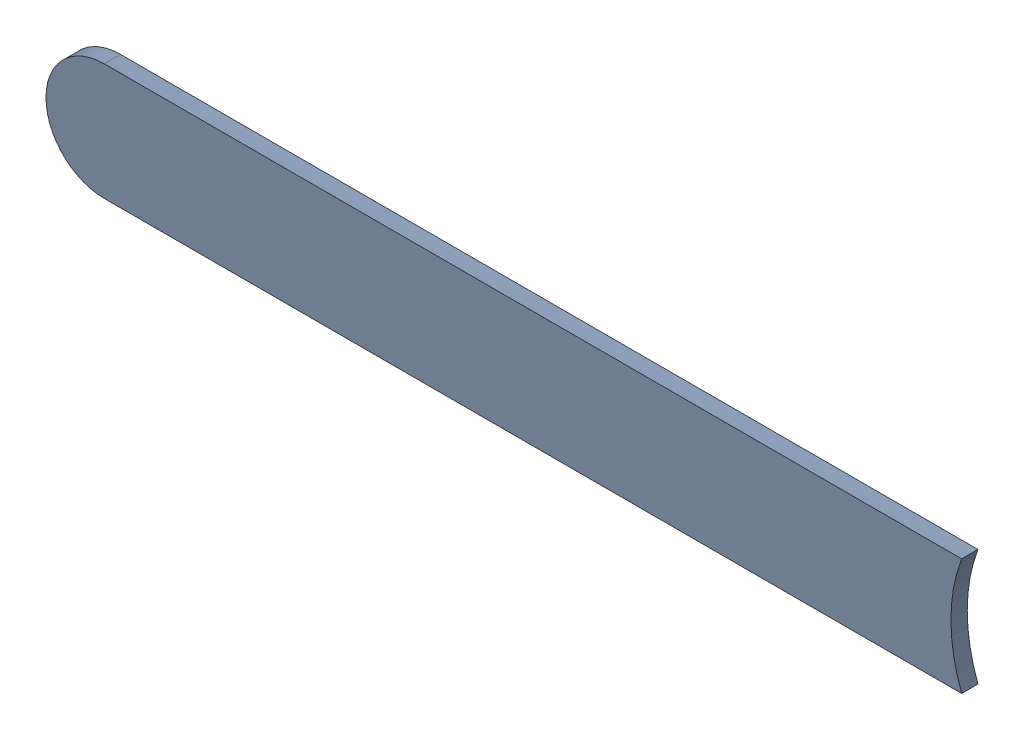
SolidWorks assembly Track (14.5mm,22.5mm)(16.7mm,22.5mm) on Top Layer, configuration Predeterminado. Lengths in mm.
Overall size (1.99 0.25 0.04).
2 component instances, 1 part files, 0 mates.
Components (placement in the parent):
- Track (14.5mm,22.5mm)(16.7mm,22.5mm) on Top Layer-1-1: Track (14.5mm,22.5mm)(16.7mm,22.5mm) on Top Layer-1 [Predeterminado] at (-68.317 -44.187 -0.0457) size (1.99 0.25 0.04)
  - Track (14.5mm,22.5mm)(16.7mm,22.5mm) on Top Layer-Part-1-1: Track (14.5mm,22.5mm)(16.7mm,22.5mm) on Top Layer-Part-1 [Predeterminado] at origin size (1.99 0.25 0.04)
